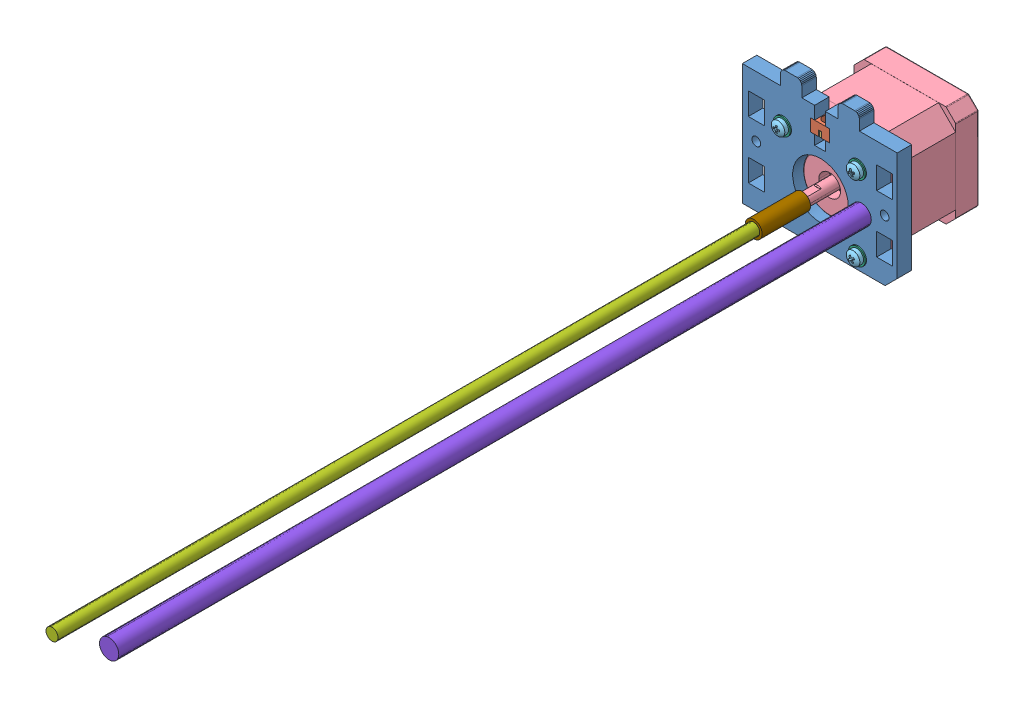
SolidWorks assembly Assembly Z-Motor Mount Bottom Right, configuration Valor predeterminado. Lengths in mm.
Overall size (64 62.65 362.01).
20 component instances, 9 part files, 23 mates.
Components (placement in the parent):
- Z-Motor Mount Bottom-1: Z-Motor Mount Bottom [Valor predeterminado] at (65.9605 -33.419 6) x (-1 0 0) z (0 0 -1) size (64 56.35 6)
- Assembly m3-nut-adapter + Nut DIN 934 - M3-1: Assembly m3-nut-adapter + Nut DIN 934 - M3 [Valor predeterminado] at (0 19.7 3) x (-1 0 0) z (0 -1 0) size (8.25 7.94 5.1)
  - m3-nut-adapter-1: m3-nut-adapter [Valor predeterminado] at origin size (8 6 5.1)
  - Nut DIN 934 - M3-1: Nut DIN 934 - M3 [Valor predeterminado] at (0 0 3.9) x (0 0 1) z (-0.866025 -0.5 0) size (2.4 5.5 6.35)
- Stepper motor Nema 17-1: Stepper motor Nema 17 [Valor predeterminado] at (24.3528 -0.0456 -12.5) x (0 0 -1) z (0 -1 0) size (62.01 42.01 48.01)
- Assembly Screw DIN 7985 - M3 x 10 --- 10N + Washer DIN 125A - M3-1: Assembly Screw DIN 7985 - M3 x 10 --- 10N + Washer DIN 125A - M3 [Valor predeterminado] at (27.2609 15.6854 3.1214) x (0 0 1) z (-0.94168 -0.33651 0) size (12.37 7 7)
  - Screw DIN 7985 - M3 x 10 --- 10N-1: Screw DIN 7985 - M3 x 10 --- 10N [Valor predeterminado] at (5.7786 -0.3419 12.3725) size (12.37 5.6 5.6)
  - Washer DIN 125A - M3-1: Washer DIN 125A - M3 [Valor predeterminado] at (2.8786 -0.3419 12.3725) size (0.5 7 7)
- Assembly Screw DIN 7985 - M3 x 10 --- 10N + Washer DIN 125A - M3-2: Assembly Screw DIN 7985 - M3 x 10 --- 10N + Washer DIN 125A - M3 [Valor predeterminado] at (23.1506 -29.7023 3.1214) x (0 0 1) z (-0.577616 0.816309 0) size (12.37 7 7)
  - Screw DIN 7985 - M3 x 10 --- 10N-1: Screw DIN 7985 - M3 x 10 --- 10N [Valor predeterminado] at (5.7786 -0.3419 12.3725) size (12.37 5.6 5.6)
  - Washer DIN 125A - M3-1: Washer DIN 125A - M3 [Valor predeterminado] at (2.8786 -0.3419 12.3725) size (0.5 7 7)
- Assembly Screw DIN 7985 - M3 x 10 --- 10N + Washer DIN 125A - M3-3: Assembly Screw DIN 7985 - M3 x 10 --- 10N + Washer DIN 125A - M3 [Valor predeterminado] at (-14.8106 -32.1686 3.1214) x (0 0 1) z (-0.009901 0.999951 0) size (12.37 7 7)
  - Screw DIN 7985 - M3 x 10 --- 10N-1: Screw DIN 7985 - M3 x 10 --- 10N [Valor predeterminado] at (5.7786 -0.3419 12.3725) size (12.37 5.6 5.6)
  - Washer DIN 125A - M3-1: Washer DIN 125A - M3 [Valor predeterminado] at (2.8786 -0.3419 12.3725) size (0.5 7 7)
- Assembly Screw DIN 7985 - M3 x 10 --- 10N + Washer DIN 125A - M3-4: Assembly Screw DIN 7985 - M3 x 10 --- 10N + Washer DIN 125A - M3 [Valor predeterminado] at (-14.8106 -1.1686 3.1214) x (0 0 1) z (-0.009901 0.999951 0) size (12.37 7 7)
  - Screw DIN 7985 - M3 x 10 --- 10N-1: Screw DIN 7985 - M3 x 10 --- 10N [Valor predeterminado] at (5.7786 -0.3419 12.3725) size (12.37 5.6 5.6)
  - Washer DIN 125A - M3-1: Washer DIN 125A - M3 [Valor predeterminado] at (2.8786 -0.3419 12.3725) size (0.5 7 7)
- Threaded Rod DIN 975 - M5 x 300-1: Threaded Rod DIN 975 - M5 x 300 [Valor predeterminado] at (0.225 -4.3 173.6) x (0.935087 -0.354418 0) z (0 0 1) size (5 5 300)
- Smooth Rod - 8 x 317-1: Smooth Rod - 8 x 317 [Valor predeterminado] at (17.225 -4.3 158.5) x (-0.057452 -0.998348 0) z (0 0 1) size (8 8 317)
- Hose shaft coupler - 7 x 20-1: Hose shaft coupler - 7 x 20 [Valor predeterminado] at (0.225 -4.3 23.6) x (0.941838 -0.336068 0) z (0 0 1) size (7 7 20)
Mates (geometry in assembly coordinates):
- Coincidente1: coincident: plane of assembly; plane of assembly; plane of Z-Motor Mount Bottom-1 through (65.9605 -33.419 0) normal (0 0 -1); plane of Assembly m3-nut-adapter + Nut DIN 934 - M3-1/m3-nut-adapter-1 through (4 14.6 0) normal (0 0 -1)
- Coincidente2: coincident: plane of assembly; plane of assembly; plane of Z-Motor Mount Bottom-1 through (-4 19.7 0) normal (1 0 0); plane of Assembly m3-nut-adapter + Nut DIN 934 - M3-1/m3-nut-adapter-1 through (-4 14.6 0) normal (-1 0 0)
- Coincidente3: coincident: plane of assembly; plane of assembly; plane of Z-Motor Mount Bottom-1 through (4 19.7 0) normal (0 -1 0); plane of Assembly m3-nut-adapter + Nut DIN 934 - M3-1/m3-nut-adapter-1 through (0 19.7 3) normal (0 1 0)
- Paralelo1: parallel: plane of assembly; plane of assembly; plane of Z-Motor Mount Bottom-1 through (26.925 -25 0) normal (0 -1 0); plane of Stepper motor Nema 17-1 through (21.225 -25.3 -7) normal (0 -1 0)
- Concêntrico2: concentric: cylinder of assembly; cylinder of assembly; cylinder of Stepper motor Nema 17-1 through (15.725 11.2 -3.5) axis (0 0 1) radius 1.5; cylinder of Assembly Screw DIN 7985 - M3 x 10 --- 10N + Washer DIN 125A - M3-1/Screw DIN 7985 - M3 x 10 --- 10N-1 through (15.725 11.2 8.9) axis (0 0 1) radius 1.5
- Concêntrico3: concentric: cylinder of assembly; cylinder of assembly; cylinder of Stepper motor Nema 17-1 through (15.725 -19.8 -3.5) axis (0 0 1) radius 1.5; cylinder of Assembly Screw DIN 7985 - M3 x 10 --- 10N + Washer DIN 125A - M3-2/Screw DIN 7985 - M3 x 10 --- 10N-1 through (15.725 -19.8 8.9) axis (0 0 1) radius 1.5
- Concêntrico4: concentric: cylinder of assembly; cylinder of assembly; cylinder of Stepper motor Nema 17-1 through (-15.275 -19.8 -3.5) axis (0 0 1) radius 1.5; cylinder of Assembly Screw DIN 7985 - M3 x 10 --- 10N + Washer DIN 125A - M3-3/Screw DIN 7985 - M3 x 10 --- 10N-1 through (-15.275 -19.8 8.9) axis (0 0 1) radius 1.5
- Concêntrico5: concentric: cylinder of assembly; cylinder of assembly; cylinder of Stepper motor Nema 17-1 through (-15.275 11.2 -3.5) axis (0 0 1) radius 1.5; cylinder of Assembly Screw DIN 7985 - M3 x 10 --- 10N + Washer DIN 125A - M3-4/Screw DIN 7985 - M3 x 10 --- 10N-1 through (-15.275 11.2 8.9) axis (0 0 1) radius 1.5
- Concêntrico6: concentric: cylinder of assembly; cylinder of assembly; cylinder of Z-Motor Mount Bottom-1 through (0.225 -4.3 0) axis (0 0 1) radius 11.5; cylinder of Stepper motor Nema 17-1 through (0.225 -4.3 0.85) axis (0 0 1) radius 11
- Coincidente10: coincident: plane of assembly; plane of assembly; plane of Z-Motor Mount Bottom-1 through (65.9605 -33.419 0) normal (0 0 -1); plane of Stepper motor Nema 17-1 through (0.225 -4.3 0) normal (0 0 1)
- Coincidente11: coincident: plane of assembly; plane of assembly; plane of Z-Motor Mount Bottom-1 through (65.9605 -33.419 6) normal (0 0 1); plane of Assembly Screw DIN 7985 - M3 x 10 --- 10N + Washer DIN 125A - M3-3/Washer DIN 125A - M3-1 through (-15.275 -19.8 6) normal (0 0 -1)
- Coincidente12: coincident: plane of assembly; plane of assembly; plane of Z-Motor Mount Bottom-1 through (65.9605 -33.419 6) normal (0 0 1); plane of Assembly Screw DIN 7985 - M3 x 10 --- 10N + Washer DIN 125A - M3-4/Washer DIN 125A - M3-1 through (-15.275 11.2 6) normal (0 0 -1)
- Coincidente13: coincident: plane of assembly; plane of assembly; plane of Z-Motor Mount Bottom-1 through (65.9605 -33.419 6) normal (0 0 1); plane of Assembly Screw DIN 7985 - M3 x 10 --- 10N + Washer DIN 125A - M3-2/Washer DIN 125A - M3-1 through (15.725 -19.8 6) normal (0 0 -1)
- Coincidente14: coincident: plane of assembly; plane of assembly; plane of Z-Motor Mount Bottom-1 through (65.9605 -33.419 6) normal (0 0 1); plane of Assembly Screw DIN 7985 - M3 x 10 --- 10N + Washer DIN 125A - M3-1/Washer DIN 125A - M3-1 through (15.725 11.2 6) normal (0 0 -1)
- Simétrico1: symmetric: plane of assembly; plane of assembly; plane of Z-Motor Mount Bottom-1 through (-22.995 16.5 0) normal (0 -1 0); plane of Z-Motor Mount Bottom-1 through (-29.595 -16.5 0) normal (0 1 0); plane of assembly
- Simétrico2: symmetric: plane of assembly; plane of assembly; plane of Z-Motor Mount Bottom-1 through (16.3 29.35 0) normal (1 0 0); plane of Z-Motor Mount Bottom-1 through (-16.3 25 0) normal (-1 0 0); plane of assembly
- Coincidente15: coincident: plane of assembly through (0 0 0) normal (0 0 1); plane of Z-Motor Mount Bottom-1 through (65.9605 -33.419 0) normal (0 0 -1); plane of assembly
- Concêntrico7: concentric: cylinder of assembly; cylinder of assembly; cylinder of Stepper motor Nema 17-1 through (0.225 -4.3 -4.4) axis (0 0 -1) radius 2.5; cylinder of Threaded Rod DIN 975 - M5 x 300-1 through (0.225 -4.3 323.6) axis (0 0 -1) radius 2.5
- Coincidente16: coincident: plane of assembly; plane of assembly; plane of Stepper motor Nema 17-1 through (24.3528 -0.0456 23.6) normal (0 0 1); plane of Threaded Rod DIN 975 - M5 x 300-1 through (0.225 -4.3 23.6) normal (0 0 -1)
- Concêntrico8: concentric: cylinder of assembly; cylinder of assembly; cylinder of Z-Motor Mount Bottom-1 through (17.225 -4.3 0) axis (0 0 1) radius 4; cylinder of Smooth Rod - 8 x 317-1 through (17.225 -4.3 317) axis (0 0 -1) radius 4
- Coincidente17: coincident: plane of assembly; plane of assembly; plane of Stepper motor Nema 17-1 through (0.225 -4.3 0) normal (0 0 1); plane of Smooth Rod - 8 x 317-1 through (17.225 -4.3 0) normal (0 0 -1)
- Concêntrico9: concentric: cylinder of Stepper motor Nema 17-1 through (0.225 -4.3 -4.4) axis (0 0 -1) radius 2.5; cylinder of ? through (0.225 -4.3 78.576) axis (0 0 -1) radius 3.5
- Coincidente18: coincident: plane of assembly; plane of assembly; plane of Stepper motor Nema 17-1 through (24.3528 -0.0456 23.6) normal (0 0 1); plane of Hose shaft coupler - 7 x 20-1 through (0.225 -4.3 23.6) normal (0 0 1)
